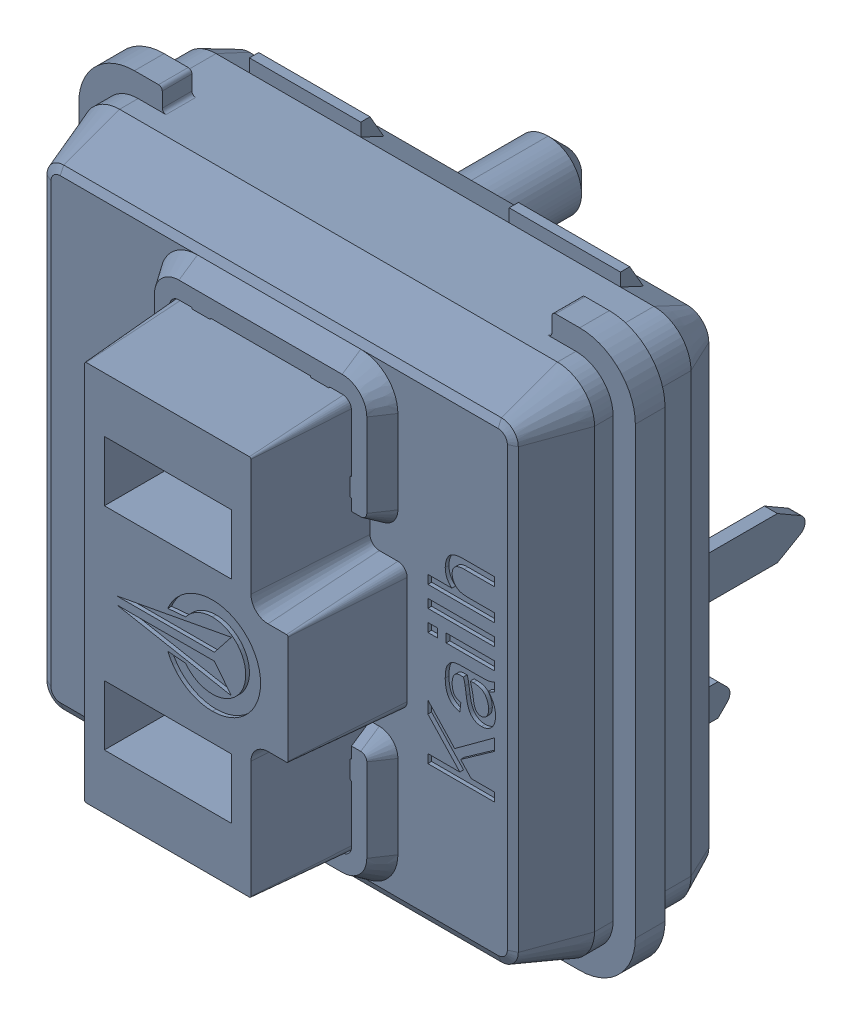
SolidWorks assembly SW7_1.step, configuration Default. Lengths in mm.
Overall size (15 15 11.1).
2 component instances, 2 part files, 0 mates.
Components (placement in the parent):
- Kailh LP Choc Burnt Orange_1.step-11: Kailh LP Choc Burnt Orange_1.step [Default] at (465.9499 258.5268 2.7) x (1 0 0) z (0 -1 0) size (15 11.1 15)
- WS2812-2020_1.step-11: WS2812-2020_1.step [Default] at (461.3087 258.6334 0.3) x (0 1 0) z (1 0 0) size (2.2 0.86 2)
